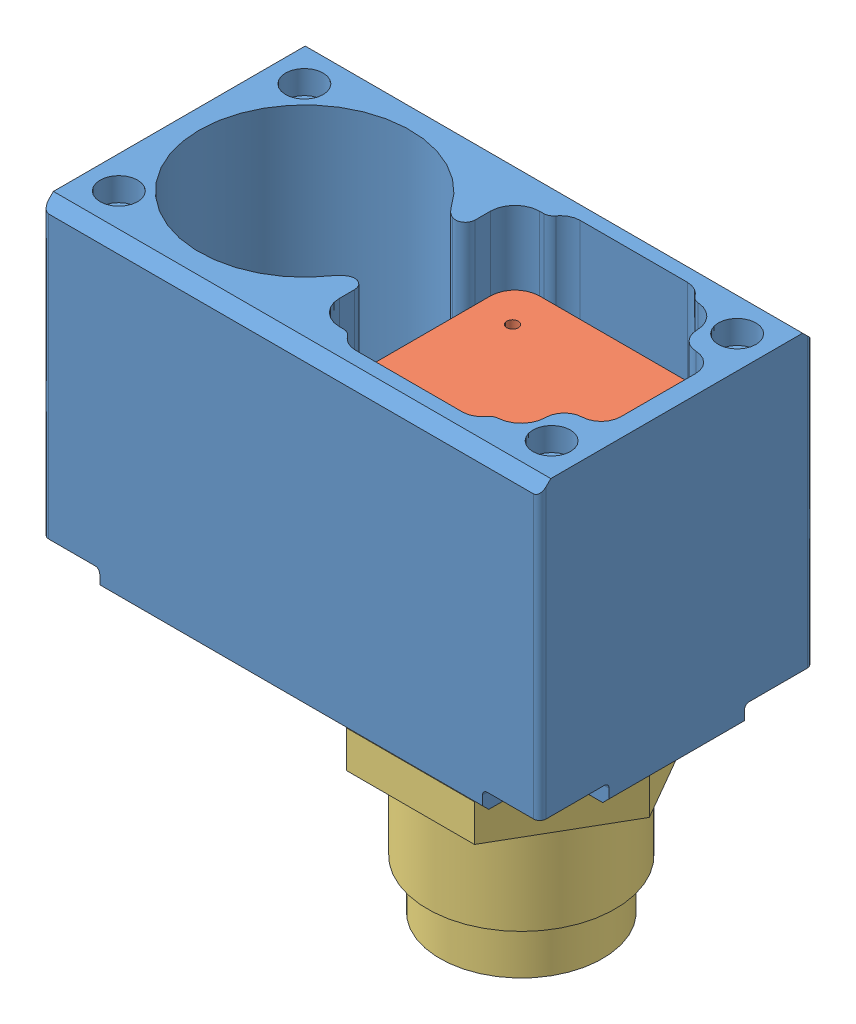
SolidWorks assembly ServoCases, configuration Default. Lengths in mm.
Overall size (40.76 41.88 27).
5 component instances, 5 part files, 38 mates.
Components (placement in the parent):
- ServoBody-1: ServoBody [Default] at origin size (40.39 25.4 22.23)
- NMEA_Connector-2: NMEA_Connector [Default] at (7.576 -4.064 0) x (0.866025 0 0.5) z (0.5 0 -0.866025) size (18.03 21.76 19.56) (hidden)
- ServoTop-1: ServoTop [Default] at (0 31.877 0) x (-1 0 0) z (0 0 -1) size (56.29 43.33 20.45) (hidden)
- ServoControlBoard-1: ServoControlBoard [Default] at (-56.1896 17.884 47.0868) size (19.5 1.68 16)
- M12A-04PFFC-SF8B15-1: M12A-04PFFC-SF8B15 [Default] at (7.576 3.524 0) x (0 -1 0) z (-0.5 0 0.866025) size (20 18 20.78)
Mates (geometry in assembly coordinates):
- Coincident2: coincident aligned: plane of ServoBody-1 through (0 25.4 0) normal (0 1 0); plane of ? through (0.6982 25.4 -37.7014) normal (0 1 0)
- Concentric1: concentric aligned: cylinder of ServoBody-1 through (7.576 25.4 0) axis (0 -1 0) radius 7.62; cylinder of NMEA_Connector-2 through (7.576 9.6901 0) axis (0 -1 0) radius 7.5565
- Coincident3: coincident anti-aligned: plane of ServoBody-1 through (0 1.524 0) normal (0 1 0); plane of NMEA_Connector-2 through (7.576 1.524 0) normal (0 -1 0)
- Concentric2: concentric aligned: cylinder of ? through (4.6833 -9.5074 -27.4769) axis (0 0 -1) radius 7.62; cylinder of ? through (4.6833 -9.5074 -38.8063) axis (0 0 -1) radius 7.5565
- Coincident4: coincident anti-aligned: plane of ? through (0.6982 -54.0367 -46.9724) normal (0 0 1); plane of ? through (4.6833 -9.5074 -46.9724) normal (0 0 -1)
- Parallel1: parallel: line of ? through (15.5779 25.4 -45.3284) axis (0 -1 0); plane of ? through (13.7003 -13.2919 -43.9752) normal (1 0 0)
- Parallel2: parallel: plane of ServoBody-1 through (-20.193 25.4 11.1125) normal (0 0 1); line of NMEA_Connector-2 through (11.3605 4.5212 -9.017) axis (-1 0 0)
- Coincident5: coincident anti-aligned: line of ServoBody-1 through (20.193 25.4 -10.2235) axis (-1 0 0); line of ServoTop-1 through (-19.685 25.4 -10.2235) axis (1 0 0)
- Coincident6: coincident anti-aligned: line of ServoBody-1 through (20.193 25.4 10.2235) axis (0 0 -1); line of ServoTop-1 through (20.193 25.4 -9.7155) axis (0 0 1)
- Coincident7: coincident anti-aligned: line of ? through (-19.4948 25.4 -47.4169) axis (0 0 1); line of ? through (-19.4948 25.4 -27.9859) axis (0 0 -1)
- Coincident8: coincident anti-aligned: line of ? through (-18.9868 25.4 -27.4779) axis (1 0 0); line of ? through (20.3832 25.4 -27.4779) axis (-1 0 0)
- Coincident9: coincident aligned: plane of ServoTop-1 through (20.0406 40.7162 10.2235) normal (1 0 0); plane of ? through (20.0406 40.7162 40.7129) normal (1 0 0)
- Coincident10: coincident aligned: plane of ServoTop-1 through (0 43.1546 0) normal (0 1 0); plane of ? through (0 43.1546 30.4894) normal (0 1 0)
- Coincident13: coincident anti-aligned: line of ? through (19.685 25.4 40.7129) axis (-1 0 0); line of ? through (-19.685 25.4 40.7129) axis (1 0 0)
- Coincident14: coincident anti-aligned: line of ? through (20.193 25.4 20.7739) axis (0 0 1); line of ? through (20.193 25.4 40.2049) axis (0 0 -1)
- Coincident15: coincident aligned: line of ? through (-19.685 9.9822 40.7129) axis (1 0 0); line of ? through (-19.685 9.9822 40.7129) axis (1 0 0)
- Coincident16: coincident aligned: line of ? through (20.193 9.9822 40.2049) axis (0 0 -1); line of ? through (20.193 9.9822 40.2049) axis (0 0 -1)
- Concentric3: concentric aligned: cylinder of ? through (6.0518 9.9822 30.4894) axis (0 -1 0) radius 7.62; cylinder of ? through (6.0518 2.1463 30.4894) axis (0 -1 0) radius 7.5565
- Coincident17: coincident anti-aligned: plane of ? through (0 -6.0198 30.4894) normal (0 1 0); plane of ? through (6.0518 -6.0198 30.4894) normal (0 -1 0)
- Parallel3: parallel aligned: plane of ? through (28.1432 34.417 20.2659) normal (0 0 -1); plane of ? through (9.8363 -3.0226 21.4724) normal (0 0 -1)
- Coincident19: coincident aligned: plane of ? through (-20.0406 40.7162 40.7129) normal (-1 0 0); plane of ? through (-20.0406 40.7162 141.1931) normal (-1 0 0)
- Coincident20: coincident aligned: plane of ? through (0 34.417 30.4894) normal (0 1 0); plane of ? through (0 34.417 130.9696) normal (0 1 0)
- Coincident21: coincident anti-aligned: line of ? through (19.685 25.4 141.1931) axis (-1 0 0); line of ? through (-19.685 25.4 141.1931) axis (1 0 0)
- Coincident22: coincident anti-aligned: line of ? through (20.193 25.4 121.2541) axis (0 0 1); line of ? through (20.193 25.4 140.6851) axis (0 0 -1)
- Coincident23: coincident aligned: line of ? through (-20.193 9.9822 120.7461) axis (0 0 1); line of ? through (-20.193 9.9822 121.2541) axis (0 0 1)
- Coincident24: coincident aligned: line of ? through (-20.193 9.9822 141.1931) axis (1 0 0); line of ? through (-19.685 9.9822 141.1931) axis (1 0 0)
- Concentric4: concentric aligned: cylinder of ? through (10.16 39.638 0) axis (0 -1 0) radius 1.75; cylinder of ? through (10.16 27.9 0) axis (0 -1 0) radius 3
- Coincident25: coincident anti-aligned: plane of ? through (10.16 27.9 0) normal (0 -1 0); plane of ? through (10.16 27.9 0) normal (0 1 0)
- Concentric5: concentric aligned: cylinder of ServoTop-1 through (10.16 47.8601 0) axis (0 -1 0) radius 2.5527; cylinder of ? through (10.16 39.638 0) axis (0 -1 0) radius 1.75
- Concentric6: concentric aligned: circle of ServoTop-1; circle of ?
- Coincident27: coincident aligned: plane of ServoTop-1 through (10.16 24.638 0) normal (0 -1 0); circle of ?
- Coincident28: coincident aligned: plane of ? through (10.16 25.4 0) normal (0 -1 0); circle of ?
- Concentric7: concentric anti-aligned: circle of ServoBody-1; cylinder of M12A-04PFFC-SF8B15-1 through (7.576 -12.476 0) axis (0 1 0) radius 7.625
- Coincident33: coincident: line of ServoBody-1 through (13.3037 1.524 8.3333) axis (0.5 0 -0.866025); plane of M12A-04PFFC-SF8B15-1 through (7.576 1.524 0) normal (0 -1 0)
- Parallel4: parallel anti-aligned: line of ServoBody-1 through (3.2231 1.524 9.127) axis (1 0 0); line of M12A-04PFFC-SF8B15-1 through (12.7721 1.524 9) axis (-1 0 0)
- Distance1: distance = 0.125 mm anti-aligned: plane of ServoBody-1 through (-1.0612 16.36 -8.125) normal (1 0 0); plane of ServoControlBoard-1 through (-0.9362 19.5604 47.0868) normal (-1 0 0)
- Distance2: distance = 0.125 mm anti-aligned: plane of ServoControlBoard-1 through (-56.1896 19.5604 8) normal (0 0 1); plane of ServoBody-1 through (-1.0612 16.36 8.125) normal (0 0 -1)
- Distance3: distance = 1.524 mm anti-aligned: plane of ServoBody-1 through (0 16.36 0) normal (0 1 0); plane of ServoControlBoard-1 through (-56.1896 17.884 47.0868) normal (0 -1 0)
